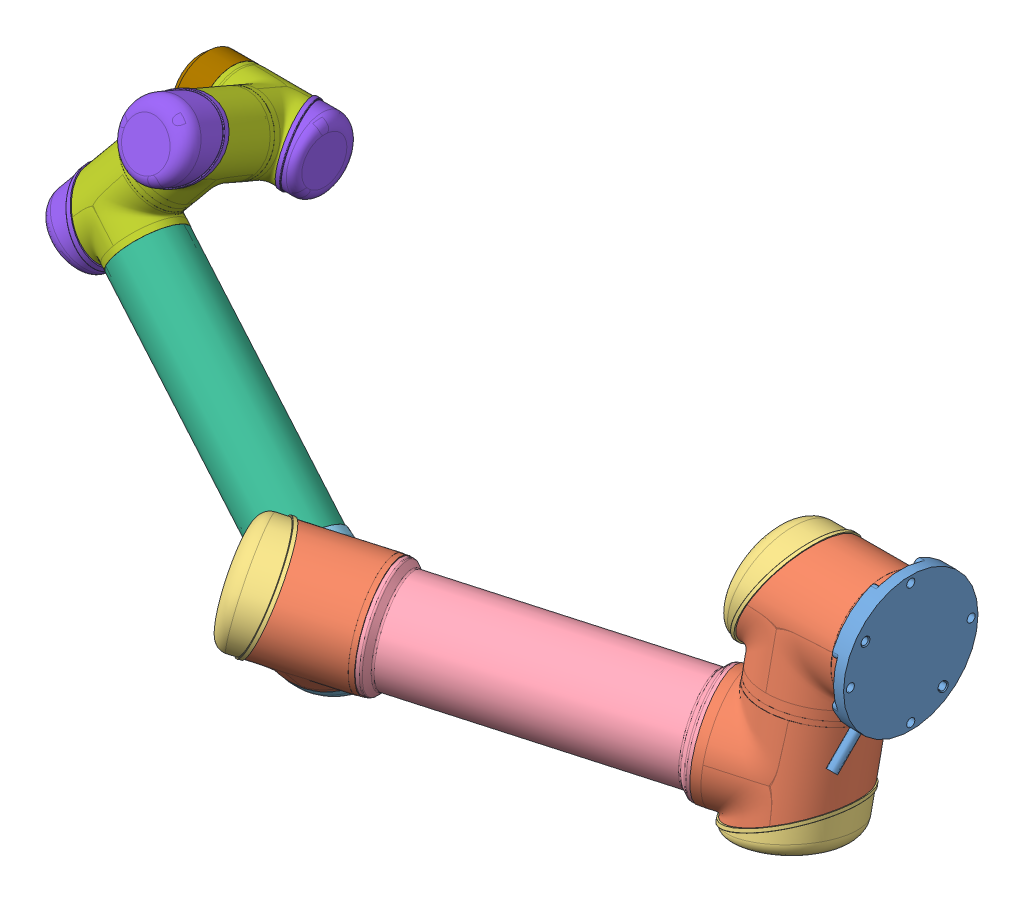
SolidWorks assembly Robot-UR-6-85-5-A, configuration Default. Lengths in mm.
Overall size (905.26 440.52 428.58).
23 component instances, 9 part files, 21 mates.
Components (placement in the parent):
- Size 3_Round base_r02_Simple-2: Size 3_Round base_r02_Simple [Default] at (-6.2377 -58.8801 -15.045) size (24 154.92 154.92)
- House big-1: House big [Default] at (-77.6679 -79.5263 -7.7887) x (1 0 0) z (0 0.205347 0.978689) size (133.98 130 124.27)
  - Size 3_House_r11_Simple-1: Size 3_House_r11_Simple [Default] at (-14.7699 21.6963 -2.862) size (129.79 128.5 124.27)
  - Size 3_Joint lid_r06_Simple-1: Size 3_Joint lid_r06_Simple [Default] at (-14.7702 21.6963 -2.862) size (62.7 119 119.01)
- House big-2: House big [Default] at (-113.6581 -176.1347 15.0229) x (0 0.978689 -0.205347) z (-0.369151 -0.190843 -0.909564) size (133.98 130 124.27)
  - Size 3_House_r11_Simple-1: Size 3_House_r11_Simple [Default] at (-14.7699 21.6963 -2.862) size (129.79 128.5 124.27)
  - Size 3_Joint lid_r06_Simple-1: Size 3_Joint lid_r06_Simple [Default] at (-14.7702 21.6963 -2.862) size (62.7 119 119.01)
- Size 3_Over arm_r01_Simpel-2: Size 3_Over arm_r01_Simpel [Default] at (-289.9288 -175.58 89.5933) x (0.92937 -0.075804 -0.361284) z (0.230272 -0.64589 0.727874) size (284 114.3 114.3)
- House big-3: House big [Default] at (-474.8214 -178.3043 147.1742) x (0.92937 -0.075804 -0.361284) z (0.20615 -0.70529 0.678284) size (133.98 130 124.27)
  - Size 3_House_r11_Simple-1: Size 3_House_r11_Simple [Default] at (-14.7699 21.6963 -2.862) size (129.79 128.5 124.27)
  - Size 3_Joint lid_r06_Simple-1: Size 3_Joint lid_r06_Simple [Default] at (-14.7702 21.6963 -2.862) size (62.7 119 119.01)
- Size 3 to Size 1_Angle_r02_Simple-2: Size 3 to Size 1_Angle_r02_Simple [Default] at (-520.7724 -247.9803 84.4704) x (0.821455 -0.535324 0.19657) z (0.481079 0.465411 -0.742937) size (132.02 97.1 116.06)
- Size 1 rør_r01_Simple-2: Size 1 rør_r01_Simple [Default] at (-704.2362 -128.421 40.5685) x (0.339286 0.735828 0.58604) z (0.821455 -0.535324 0.19657) size (75 75 272.93)
- House small-1: House small [Default] at (-811.1705 -46.0123 25.0094) x (0.821455 -0.535324 0.19657) z (-0.024077 -0.376943 -0.925923) size (84.25 104.71 77.52)
  - Size 1_House_r13_Simple-1: Size 1_House_r13_Simple [Default] at (-34.0745 6.3813 14.0822) size (83 87.5 75.48)
  - Size 1_Joint lid_r07_Simple-1: Size 1_Joint lid_r07_Simple [Default] at (-34.0745 6.3813 14.0822) size (77.5 51.3 77.52)
- House small-2: House small [Default] at (-797.9895 -3.2471 -14.3951) x (-0.569765 -0.755872 0.322531) z (-0.821808 0.524051 -0.223613) size (84.25 104.71 77.52)
  - Size 1_House_r13_Simple-1: Size 1_House_r13_Simple [Default] at (-34.0745 6.3813 14.0822) size (83 87.5 75.48)
  - Size 1_Joint lid_r07_Simple-1: Size 1_Joint lid_r07_Simple [Default] at (-34.0745 6.3813 14.0822) size (77.5 51.3 77.52)
- House small-3: House small [Default] at (-796.5293 -3.6856 -71.3358) x (0 0.392465 0.919767) z (0 0.919767 -0.392465) size (84.25 104.71 77.52)
  - Size 1_House_r13_Simple-1: Size 1_House_r13_Simple [Default] at (-34.0745 6.3813 14.0822) size (83 87.5 75.48)
  - Size 1_Joint lid_r07_Simple-1: Size 1_Joint lid_r07_Simple [Default] at (-34.0745 6.3813 14.0822) size (77.5 51.3 77.52)
- Size 1_Tool flange_r03_Simple-2: Size 1_Tool flange_r03_Simple [Default] at (-837.648 -4.1062 -108.2032) x (-1 0 0) z (0 0.974345 -0.225059) size (34.5 80.5 75)
Mates (geometry in assembly coordinates):
- Coincident3: coincident anti-aligned: plane of Size 3_Round base_r02_Simple-2 through (-27.2377 -2.7801 -15.045) normal (-1 0 0); plane of House big-1/Size 3_House_r11_Simple-1 through (-27.2377 -58.8801 -15.045) normal (1 0 0)
- Concentric3: concentric anti-aligned: circle of Size 3_Round base_r02_Simple-2; circle of House big-1/Size 3_House_r11_Simple-1
- Coincident4: coincident anti-aligned: plane of House big-1/Size 3_House_r11_Simple-1 through (-92.4377 -127.8777 -0.5681) normal (0 -0.978689 0.205347); plane of House big-2/Size 3_House_r11_Simple-1 through (-92.4377 -127.8777 -0.5681) normal (0 0.978689 -0.205347)
- Concentric4: concentric anti-aligned: circle of House big-1/Size 3_House_r11_Simple-1; circle of House big-2/Size 3_House_r11_Simple-1
- Coincident5: coincident anti-aligned: plane of House big-2/Size 3_House_r11_Simple-1 through (-157.9583 -186.3441 38.291) normal (-0.92937 0.075804 0.361284); plane of Size 3_Over arm_r01_Simpel-2 through (-174.4042 -229.6446 5.0706) normal (0.92937 -0.075804 -0.361284)
- Concentric5: concentric anti-aligned: circle of House big-2/Size 3_House_r11_Simple-1; circle of Size 3_Over arm_r01_Simpel-2
- Coincident6: coincident anti-aligned: plane of Size 3_Over arm_r01_Simpel-2 through (-438.3452 -208.1163 107.6752) normal (-0.92937 0.075804 0.361284); plane of House big-3/Size 3_House_r11_Simple-1 through (-421.8993 -164.8158 140.8956) normal (0.92937 -0.075804 -0.361284)
- Concentric6: concentric anti-aligned: circle of Size 3_Over arm_r01_Simpel-2; circle of House big-3/Size 3_House_r11_Simple-1
- Coincident7: coincident anti-aligned: plane of House big-3/Size 3_House_r11_Simple-1 through (-504.0831 -209.5657 119.3421) normal (-0.306226 -0.704855 -0.639848); plane of Size 3 to Size 1_Angle_r02_Simple-2 through (-504.0831 -209.5657 119.3421) normal (0.306226 0.704855 0.639848)
- Coincident8: coincident aligned: circle of House big-3/Size 3_House_r11_Simple-1; circle of Size 3 to Size 1_Angle_r02_Simple-2
- Coincident9: coincident anti-aligned: plane of Size 3 to Size 1_Angle_r02_Simple-2 through (-581.5601 -208.3663 69.9242) normal (-0.821455 0.535324 -0.19657); plane of Size 1 rør_r01_Simple-2 through (-581.5601 -208.3663 69.9242) normal (0.821455 -0.535324 0.19657)
- Concentric7: concentric anti-aligned: circle of Size 3 to Size 1_Angle_r02_Simple-2; circle of Size 1 rør_r01_Simple-2
- Coincident12: coincident anti-aligned: plane of Size 1 rør_r01_Simple-2 through (-822.9485 -77.812 45.7524) normal (-0.821455 0.535324 -0.19657); plane of House small-1/Size 1_House_r13_Simple-1 through (-805.7599 -62.2603 16.2744) normal (0.821455 -0.535324 0.19657)
- Coincident13: coincident aligned: circle of Size 1 rør_r01_Simple-2; circle of House small-1/Size 1_House_r13_Simple-1
- Coincident14: coincident anti-aligned: plane of House small-1/Size 1_House_r13_Simple-1 through (-816.0723 -1.9991 -7.9897) normal (0.569765 0.755872 -0.322531); plane of House small-2/Size 1_House_r13_Simple-1 through (-816.0723 -1.9991 -7.9897) normal (-0.569765 -0.755872 0.322531)
- Concentric8: concentric aligned: circle of House small-1/Size 1_House_r13_Simple-1; circle of House small-2/Size 1_House_r13_Simple-1
- Coincident16: coincident anti-aligned: plane of House small-2/Size 1_House_r13_Simple-1 through (-790.148 13.7509 -66.3538) normal (0 -0.392465 -0.919767); plane of House small-3/Size 1_House_r13_Simple-1 through (-790.148 13.7509 -66.3538) normal (0 0.392465 0.919767)
- Concentric9: concentric aligned: circle of House small-2/Size 1_House_r13_Simple-1; circle of House small-3/Size 1_House_r13_Simple-1
- Coincident17: coincident anti-aligned: plane of House small-3/Size 1_House_r13_Simple-1 through (-837.648 -4.1062 -108.2032) normal (-1 0 0); plane of Size 1_Tool flange_r03_Simple-2 through (-837.648 4.3335 -71.6652) normal (1 0 0)
- Concentric10: concentric anti-aligned: circle of House small-3/Size 1_House_r13_Simple-1; circle of Size 1_Tool flange_r03_Simple-2
- Parallel1: parallel anti-aligned: plane of Size 3_Round base_r02_Simple-2 through (-3.2377 14.6199 -15.045) normal (1 0 0); plane of Size 1_Tool flange_r03_Simple-2 through (-872.148 2.9831 -77.5113) normal (-1 0 0)
